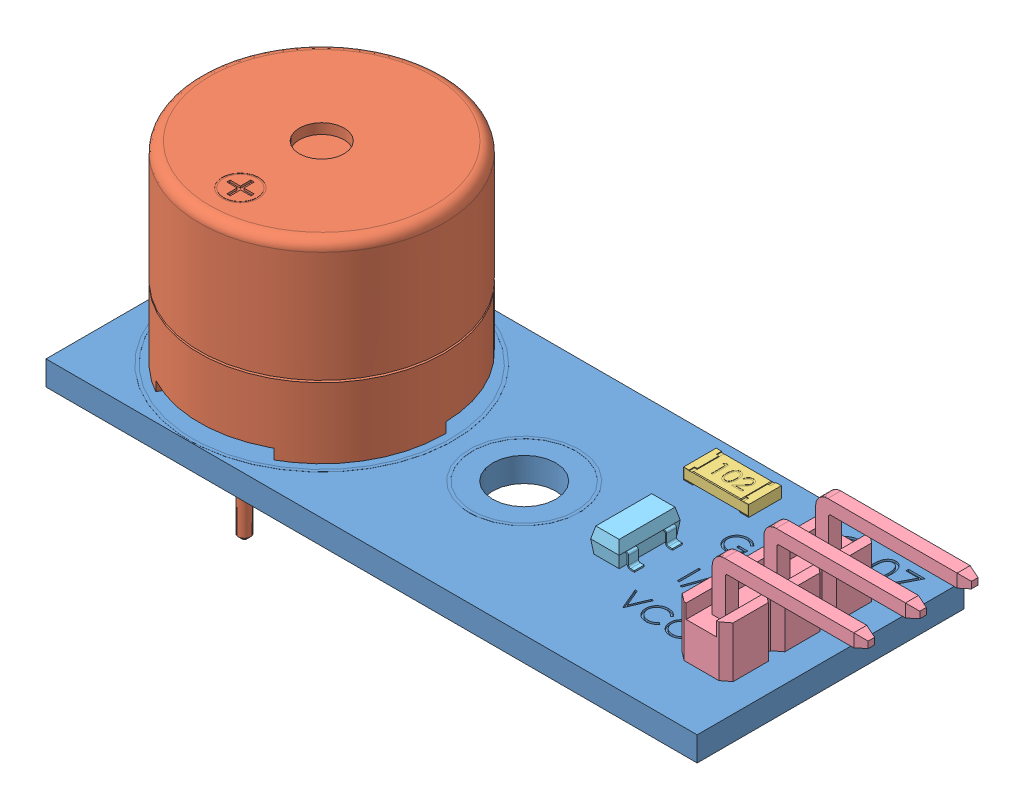
SolidWorks assembly Buzzer Module - FC-07, configuration Default. Lengths in mm.
Overall size (36.55 15 13.1).
5 component instances, 5 part files, 12 mates.
Components (placement in the parent):
- Buzzer Module - FC-07 - PCB-1: Buzzer Module - FC-07 - PCB [Default] at origin size (32 1.2 13.1)
- Buzzer - 7.6mm-1: Buzzer - 7.6mm [Default] at (-9 1.2 0) x (-1 0 0) z (0 1 0) size (12 12 15)
- Resistor - SMD - 1206-1: Resistor - SMD - 1206 [Resistor - SMD - 1206 - 1K] at (6.4157 1.2 -4.7683) x (1 0 0) z (0 1 0) size (3.2 1.6 0.55)
- Pin Header - Single Row - Angled - 2.54 - 3x1-1: Pin Header - Single Row - Angled - 2.54 - 3x1 [Default] at (13.37 3.7 0) x (0 0 1) z (-1 0 0) size (7.42 8 8.43)
- Transistör - SMD - BC817 NPN - SOT23-1: Transistör - SMD - BC817 NPN - SOT23 [Predeterminado] at (6.4157 1.8726 0) x (0 0 -1) z (0 1 0) size (3 2.25 1.22)
Mates (geometry in assembly coordinates):
- Coincident2: coincident anti-aligned: plane of Buzzer Module - FC-07 - PCB-1 through (0 1.2 0) normal (0 1 0); plane of Resistor - SMD - 1206-1 through (6.4157 1.2 -4.7683) normal (0 -1 0)
- Concentric3: concentric anti-aligned: cylinder of Buzzer Module - FC-07 - PCB-1 through (13.37 -0.001 -2.54) axis (0 1 0) radius 0.4; cylinder of Pin Header - Single Row - Angled - 2.54 - 3x1-1 through (13.37 -2.2 -2.54) axis (0 -1 0) radius 0.1
- Coincident3: coincident anti-aligned: plane of Buzzer Module - FC-07 - PCB-1 through (0 1.2 0) normal (0 1 0); plane of Pin Header - Single Row - Angled - 2.54 - 3x1-1 through (13.37 1.2 -0.7112) normal (0 -1 0)
- Parallel1: parallel aligned: plane of Buzzer Module - FC-07 - PCB-1 through (16 1.2 -6.55) normal (1 0 0); plane of Pin Header - Single Row - Angled - 2.54 - 3x1-1 through (14.62 1.2 -0.8639) normal (1 0 0)
- Coincident4: coincident anti-aligned: plane of Buzzer Module - FC-07 - PCB-1 through (0 1.2 0) normal (0 1 0); plane of Transistör - SMD - BC817 NPN - SOT23-1 through (5.4746 1.2 -1.512) normal (0 -1 0)
- Width1: width aligned: plane of Buzzer Module - FC-07 - PCB-1 through (-16 1.2 6.55) normal (0 0 1); plane of Buzzer Module - FC-07 - PCB-1 through (-16 1.2 -6.55) normal (0 0 -1); plane of Transistör - SMD - BC817 NPN - SOT23-1 through (5.29 1.1826 0.2418) normal (0 0 1); plane of Transistör - SMD - BC817 NPN - SOT23-1 through (5.8427 1.1826 -0.2418) normal (0 0 -1)
- Distance1: distance = 1 mm aligned: plane of Resistor - SMD - 1206-1 through (6.4157 1.2 -5.55) normal (0 0 -1); plane of Buzzer Module - FC-07 - PCB-1 through (-16 1.2 -6.55) normal (0 0 -1)
- Distance2: distance = 2.79 mm: plane of Transistör - SMD - BC817 NPN - SOT23-1 through (5.29 1.1826 -0.2418) normal (-1 0 0); cylinder of Buzzer Module - FC-07 - PCB-1 through (0.95 -0.001 0) axis (0 1 0) radius 1.55
- Width2: width anti-aligned: plane of Resistor - SMD - 1206-1 through (4.8157 1.2 -4.7683) normal (-1 0 0); plane of Resistor - SMD - 1206-1 through (8.0157 1.2 -4.7683) normal (1 0 0); plane of Transistör - SMD - BC817 NPN - SOT23-1 through (7.5415 1.1826 -0.6945) normal (1 0 0); plane of Transistör - SMD - BC817 NPN - SOT23-1 through (5.29 1.1826 -0.2418) normal (-1 0 0)
- Concentric4: concentric anti-aligned: cylinder of Buzzer Module - FC-07 - PCB-1 through (-9 -0.001 3.8) axis (0 1 0) radius 0.4; cylinder of Buzzer - 7.6mm-1 through (-9 1.7 3.8) axis (0 -1 0) radius 0.3
- Concentric5: concentric anti-aligned: cylinder of Buzzer Module - FC-07 - PCB-1 through (-9 -0.001 -3.8) axis (0 1 0) radius 0.4; cylinder of Buzzer - 7.6mm-1 through (-9 1.7 -3.8) axis (0 -1 0) radius 0.3
- Coincident6: coincident anti-aligned: plane of Buzzer Module - FC-07 - PCB-1 through (0 1.2 0) normal (0 1 0); plane of Buzzer - 7.6mm-1 through (-9 1.2 0) normal (0 -1 0)
